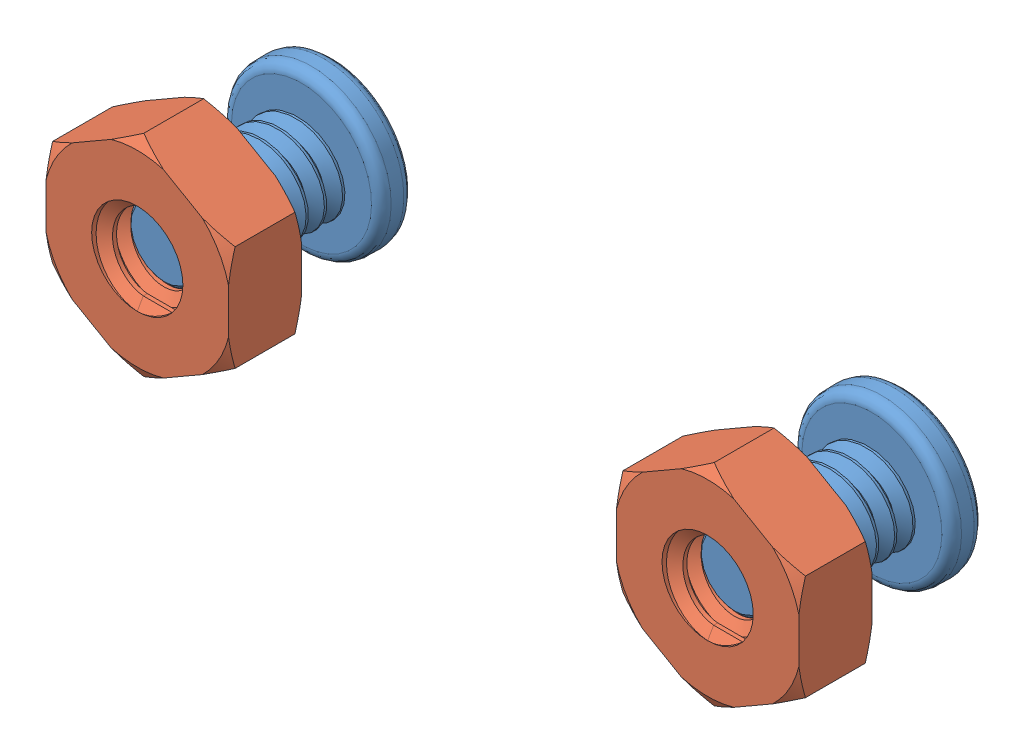
SolidWorks assembly BU, configuration Predeterminado. Lengths in mm.
Overall size (17.07 4.62 8.6).
5 component instances, 3 part files, 10 mates.
Components (placement in the parent):
- buzzer-1: buzzer [Predeterminado] at (154.9902 -224.4737 140.9608) x (0 1 0) z (0 0 -1) (suppressed, hidden)
- (M2_5_mm)_90116A009_METRIC 316 SS PAN HEAD PHILLIPS MACHINE SCREW-2: (M2_5_mm)_90116A009_METRIC 316 SS PAN HEAD PHILLIPS MACHINE SCREW [90116A009] at (153.5972 -225.5867 142.9608) x (-0.923728 -0.383049 0) z (0 0 -1) size (3.5 3.5 8.6)
- (M2_5_mm)_90116A009_METRIC 316 SS PAN HEAD PHILLIPS MACHINE SCREW-3: (M2_5_mm)_90116A009_METRIC 316 SS PAN HEAD PHILLIPS MACHINE SCREW [90116A009] at (166.0972 -225.5867 142.9608) x (-0.923728 -0.383049 0) z (0 0 -1) size (3.5 3.5 8.6)
- porca sextavada iso 4032 - m2-1: porca sextavada iso 4032 - m2 [Predeterminado] at (153.5972 -225.5867 141.9608) size (4 4.62 1.68)
- porca sextavada iso 4032 - m2-2: porca sextavada iso 4032 - m2 [Predeterminado] at (166.0972 -225.5867 141.9608) size (4 4.62 1.68)
Mates (geometry in assembly coordinates):
- Coincidente1: coincident: plane of buzzer-1 through (154.9902 -224.4737 137.7994) normal (0 0 -1); plane of ? through (157.2063 -232.5205 137.7994) normal (0 0 1)
- Coincidente2: coincident: plane of buzzer-1 through (154.9902 -224.4737 139.9608) normal (0 0 -1); plane of ? through (152.9053 -245.1703 139.9608) normal (0 0 1)
- Coincidente3: coincident: plane of buzzer-1 through (154.9902 -224.4737 139.9608) normal (0 0 -1); plane of (M2_5_mm)_90116A009_METRIC 316 SS PAN HEAD PHILLIPS MACHINE SCREW-2 through (153.5972 -225.5867 139.9608) normal (0 0 1)
- Concéntrica1: concentric: circle of buzzer-1; circle of (M2_5_mm)_90116A009_METRIC 316 SS PAN HEAD PHILLIPS MACHINE SCREW-2
- Coincidente4: coincident: plane of buzzer-1 through (154.9902 -224.4737 139.9608) normal (0 0 -1); plane of (M2_5_mm)_90116A009_METRIC 316 SS PAN HEAD PHILLIPS MACHINE SCREW-3 through (166.0972 -225.5867 139.9608) normal (0 0 1)
- Concéntrica2: concentric: circle of buzzer-1; circle of (M2_5_mm)_90116A009_METRIC 316 SS PAN HEAD PHILLIPS MACHINE SCREW-3
- Distancia1: distance = 1 mm: plane of porca sextavada iso 4032 - m2-1 through (153.5972 -225.5867 141.9608) normal (0 0 -1); plane of buzzer-1 through (154.9902 -224.4737 140.9608) normal (0 0 1)
- Concéntrica3: concentric: circle of buzzer-1; circle of porca sextavada iso 4032 - m2-1
- Distancia2: distance = 1 mm: plane of porca sextavada iso 4032 - m2-2 through (166.0972 -225.5867 141.9608) normal (0 0 -1); plane of buzzer-1 through (154.9902 -224.4737 140.9608) normal (0 0 1)
- Concéntrica4: concentric: circle of buzzer-1; circle of porca sextavada iso 4032 - m2-2
